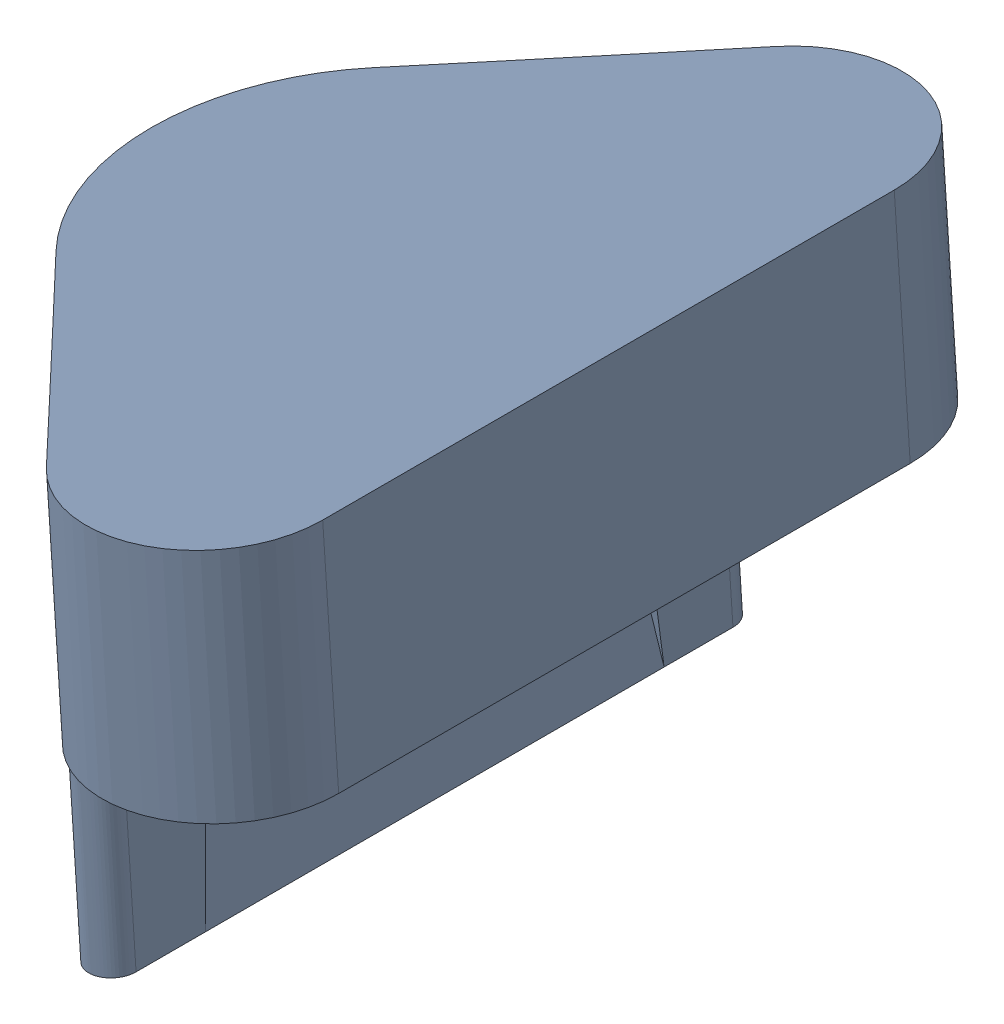
SolidWorks assembly switch assem, configuration Default. Lengths in mm.
Overall size (4.27 4.27 6.98).
2 component instances, 2 part files, 3 mates.
Components (placement in the parent):
- limit switch-1: limit switch [Standard] at (-3.1507 -2.9056 -8.6093) (suppressed, hidden)
- limitcover-1: limitcover [Default] at (-14.7464 6.3651 -8.3296) x (0 0 1) z (0.069663 -0.997571 0) size (6.98 4 4)
Mates (geometry in assembly coordinates):
- Coincident1: coincident anti-aligned: plane of limit switch-1 through (-14.1507 -6.9056 -1.6093) normal (-0.974391 -0.22486 0); plane of limitcover-1 through (-16.2634 2.2494 -5.3296) normal (0.974391 0.22486 0)
- Coincident2: coincident aligned: line of limit switch-1 through (-17.1507 6.0944 -1.6093) axis (0 0 -1); line of limitcover-1 through (-17.1507 6.0944 -1.6093) axis (0 0 -1)
- Coincident5: coincident: point of limit switch-1; point of limitcover-1
